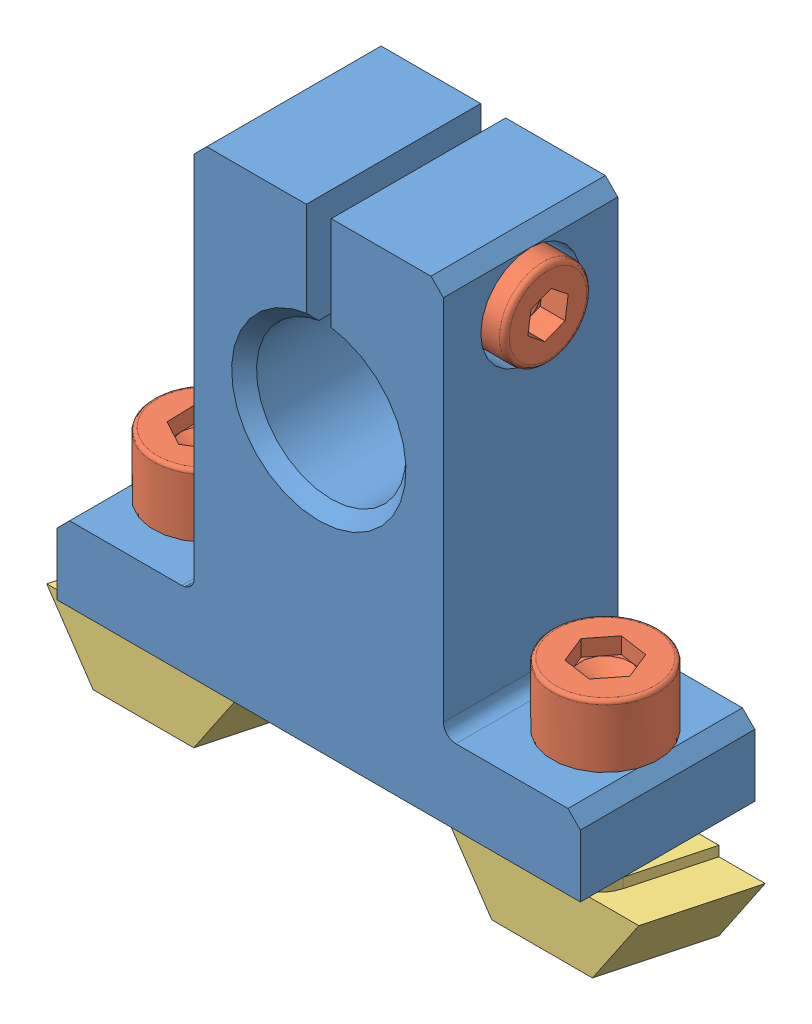
SolidWorks assembly Assem2, configuration Default. Lengths in mm.
Overall size (49.67 45.5 15.76).
6 component instances, 3 part files, 12 mates.
Components (placement in the parent):
- SK12 SHA12 Shaft support-1: SK12 SHA12 Shaft support [Default] at (-34.9557 -4.0132 -7) size (42 37.5 14)
- Socket head cap screw-1: Socket head cap screw [M4x15] at (-23.5557 28.4868 0) x (-1 0 0) z (0 -0.784402 0.620253) size (19 7 7)
- Socket head cap screw-3: Socket head cap screw [M5x14] at (-50.9557 6.9868 0) x (0 -1 0) z (0.475918 0 -0.879489) size (19 8.5 8.5)
- Socket head cap screw-4: Socket head cap screw [M5x14] at (-18.9557 6.9868 0) x (0 -1 0) z (-0.141815 0 0.989893) size (19 8.5 8.5)
- HNTF6-5-1: HNTF6-5 [Default] at (-50.9557 -5.5132 0) x (0 1 0) z (-0.258819 0 0.965926) size (6.3 15 12.3)
- HNTF6-5-2: HNTF6-5 [Default] at (-18.9557 -5.5132 0) x (0 1 0) z (-0.258819 0 0.965926) size (6.3 15 12.3)
Mates (geometry in assembly coordinates):
- Concentric1: concentric aligned: cylinder of SK12 SHA12 Shaft support-1 through (-24.9557 28.4868 0) axis (1 0 0) radius 2.25; cylinder of Socket head cap screw-1 through (8.1943 28.4868 0) axis (1 0 0) radius 2
- Coincident1: coincident anti-aligned: plane of SK12 SHA12 Shaft support-1 through (-27.5557 30.7368 0) normal (1 0 0); plane of Socket head cap screw-1 through (-27.5557 26.3159 -2.7454) normal (-1 0 0)
- Concentric2: concentric aligned: cylinder of SK12 SHA12 Shaft support-1 through (-50.9557 1.9868 0) axis (0 1 0) radius 2.75; cylinder of Socket head cap screw-3 through (-50.9557 38.7368 0) axis (0 1 0) radius 2.5
- Coincident2: coincident anti-aligned: plane of SK12 SHA12 Shaft support-1 through (-55.9557 1.9868 7) normal (0 1 0); plane of Socket head cap screw-3 through (-54.6936 1.9868 -2.0227) normal (0 -1 0)
- Concentric3: concentric aligned: cylinder of SK12 SHA12 Shaft support-1 through (-18.9557 1.9868 0) axis (0 1 0) radius 2.75; cylinder of Socket head cap screw-4 through (-18.9557 38.7368 0) axis (0 1 0) radius 2.5
- Coincident3: coincident aligned: plane of SK12 SHA12 Shaft support-1 through (-13.9557 1.9868 7) normal (0 1 0); circle of Socket head cap screw-4
- Concentric4: concentric aligned: cylinder of Socket head cap screw-3 through (-50.9557 38.7368 0) axis (0 1 0) radius 2.5; circle of HNTF6-5-1
- Parallel1: parallel aligned: plane of SK12 SHA12 Shaft support-1 through (-34.9557 18.9868 7) normal (0 0 1); plane of HNTF6-5-1 through (-56.0651 -6.3132 4) normal (0 0 1)
- Distance1: distance = 1.5 mm anti-aligned: plane of HNTF6-5-1 through (-51.9265 -5.5132 -1.4) normal (0 1 0); plane of SK12 SHA12 Shaft support-1 through (-13.9557 -4.0132 7) normal (0 -1 0)
- Concentric5: concentric aligned: cylinder of Socket head cap screw-4 through (-18.9557 38.7368 0) axis (0 1 0) radius 2.5; circle of HNTF6-5-2
- Parallel2: parallel aligned: plane of SK12 SHA12 Shaft support-1 through (-34.9557 18.9868 7) normal (0 0 1); plane of HNTF6-5-2 through (-24.0651 -6.3132 4) normal (0 0 1)
- Distance2: distance = 1.5 mm anti-aligned: plane of HNTF6-5-2 through (-19.9265 -5.5132 -1.4) normal (0 1 0); plane of SK12 SHA12 Shaft support-1 through (-13.9557 -4.0132 7) normal (0 -1 0)
